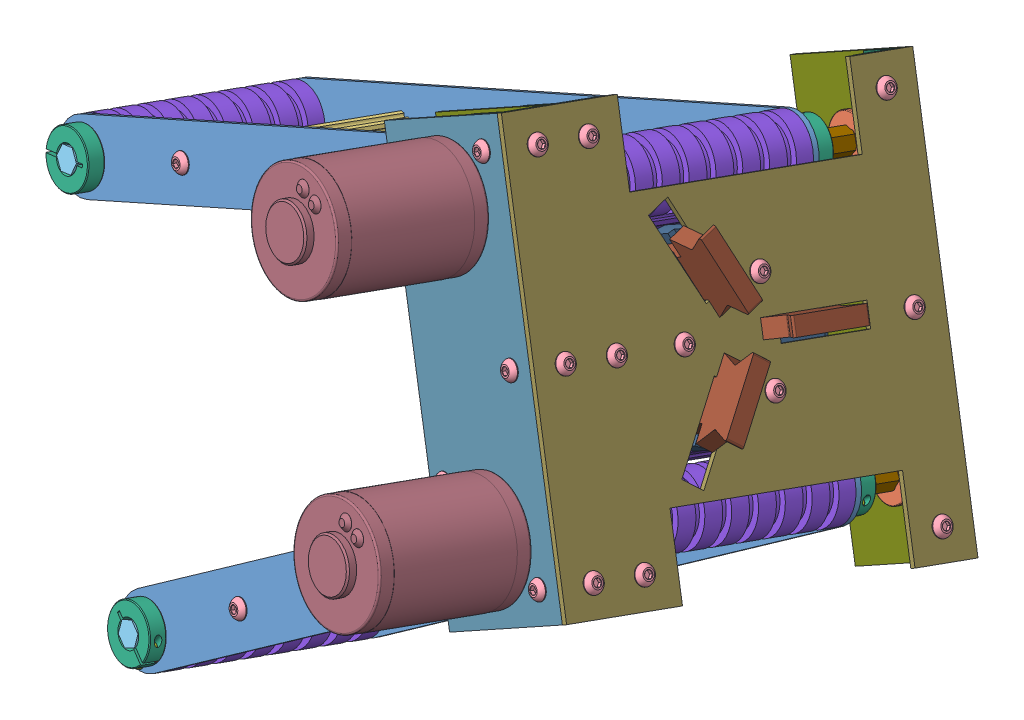
SolidWorks assembly 1504_Deep_Space_Intake_Prototype_21, configuration Default. Lengths in mm.
Overall size (546.37 581.13 450.16).
127 component instances, 18 part files, 4 mates.
Components (placement in the parent):
- Arm_Assembly-1: Arm_Assembly [Default] at (-225.8877 51.6666 438.0477) x (0.575434 0.811998 -0.097649) z (-0.800065 0.534132 -0.273127) size (386.7 241.43 173.84)
  - Arms_Top_Bottom_Plate-1: Arms_Top_Bottom_Plate [Default] at (-277.9606 169.7769 222.1703) x (-0.345233 0 -0.938517) z (0 -1 0) size (38.57 397.35 3.17)
  - 1_2_Hex_Bore_Flange_Bearing-1: 1_2_Hex_Bore_Flange_Bearing [Default] at (58.7558 163.3736 98.3094) x (0.284409 0 0.958703) z (0 1 0) size (31.12 31.12 7.93)
  - 1_2_Hex_Bore_Flange_Bearing-2: 1_2_Hex_Bore_Flange_Bearing [Default] at (-277.9606 163.3736 222.1703) x (-0.84433 0 -0.535824) z (0 1 0) size (31.12 31.12 7.93)
  - 1_2_Hex_Bore_Flange_Bearing-3: 1_2_Hex_Bore_Flange_Bearing [Default] at (-277.9606 49.4043 222.1703) x (0.84433 0 0.535824) z (0 -1 0) size (31.12 31.12 7.93)
  - 1_2_Hex_Bore_Flange_Bearing-4: 1_2_Hex_Bore_Flange_Bearing [Default] at (58.7558 49.4043 98.3094) x (-0.284409 0 -0.958703) z (0 -1 0) size (31.12 31.12 7.93)
  - Arms_Top_Bottom_Plate-2: Arms_Top_Bottom_Plate [Default] at (-277.9606 43.0009 222.1703) x (0.345233 0 0.938517) z (0 1 0) size (38.57 397.35 3.17)
  - 1_2_5__Churro_Tube-1: 1_2_5__Churro_Tube [Default] at (-209.5369 98.8759 197.0007) x (-0.345233 0 -0.938517) z (0 1 0) size (14.66 12.7 120.43)
  - 1_2_5__Churro_Tube-2: 1_2_5__Churro_Tube [Default] at (-109.6024 98.8759 160.2399) x (-0.345233 0 -0.938517) z (0 1 0) size (14.66 12.7 120.43)
  - 1_2_5__Churro_Tube-3: 1_2_5__Churro_Tube [Default] at (-9.6679 98.8759 123.479) x (-0.345233 0 -0.938517) z (0 1 0) size (14.66 12.7 120.43)
  - 1_4-20_1_2_Button_Cap-1: 1_4-20_1_2_Button_Cap [Default] at (-9.6679 173.1297 123.479) x (-0.345233 0 -0.938517) z (0 1 0) size (11.17 11.22 17.01)
  - 1_4-20_1_2_Button_Cap-2: 1_4-20_1_2_Button_Cap [Default] at (-109.6024 173.1297 160.2399) x (-0.345233 0 -0.938517) z (0 1 0) size (11.17 11.22 17.01)
  - 1_4-20_1_2_Button_Cap-3: 1_4-20_1_2_Button_Cap [Default] at (-209.5369 173.1297 197.0007) x (-0.345233 0 -0.938517) z (0 1 0) size (11.17 11.22 17.01)
  - 1_4-20_1_2_Button_Cap-4: 1_4-20_1_2_Button_Cap [Default] at (-9.6679 39.6481 123.479) x (-0.345233 0 -0.938517) z (0 -1 0) size (11.17 11.22 17.01)
  - 1_4-20_1_2_Button_Cap-5: 1_4-20_1_2_Button_Cap [Default] at (-109.6024 39.6481 160.2399) x (-0.345233 0 -0.938517) z (0 -1 0) size (11.17 11.22 17.01)
  - 1_4-20_1_2_Button_Cap-6: 1_4-20_1_2_Button_Cap [Default] at (-209.5369 39.6481 197.0007) x (-0.345233 0 -0.938517) z (0 -1 0) size (11.17 11.22 17.01)
  - 0.5_Hex_Shaft_Idle-1: 0.5_Hex_Shaft_Idle [Default] at (-271.2056 40.7057 219.3585) x (-0.384298 0 -0.923209) z (0.923209 0 -0.384298) size (13.49 146 14.63)
  - 1_2_Hex_Shaft_Collar-1: 1_2_Hex_Shaft_Collar [Default] at (127.7816 408.0678 12.6986) size (42.94 10.19 42.95)
    - am-1238 Clamp Only-1: am-1238 Clamp Only [Default] at (-405.7309 -236.7669 209.4653) x (0.868523 0 -0.495649) z (0.495649 0 0.868523) size (31.47 10.19 31.5)
    - am-1238 Screw Only_91251A194-1: am-1238 Screw Only_91251A194 [Default] at (-392.5372 -232.0044 210.8557) x (0.868523 0 -0.495649) z (0.495649 0 0.868523) size (6.86 6.86 17.11)
  - 1_2_Hex_Shaft_Collar_1-1: 1_2_Hex_Shaft_Collar_1 [Default] at (75.9024 412.9384 -146.8237) size (32.06 10.19 32.03)
    - am-1238 Clamp Only-1: am-1238 Clamp Only [Default] at (-353.863 -379.4625 368.9941) x (0.017972 0 -0.999838) z (0.999838 0 0.017972) size (31.47 10.19 31.5)
    - am-1238 Screw Only_91251A194-1: am-1238 Screw Only_91251A194 [Default] at (-345.9237 -374.7 358.3651) x (0.017972 0 -0.999838) z (0.999838 0 0.017972) size (6.86 6.86 17.11)
  - Belt_Hub-1: Belt_Hub [Default] at (-277.9606 48.8891 222.1703) x (-0.384298 0 -0.923209) z (0 1 0) size (38.57 38.57 113.97)
  - 0.5_Hex_Shaft_Drive-1: 0.5_Hex_Shaft_Drive [Default] at (51.8162 4.5177 95.9906) x (-0.316916 0 0.948454) z (-0.948454 0 -0.316916) size (13.49 241.43 14.63)
  - Belt_Hub-2: Belt_Hub [Default] at (58.7558 52.1174 98.3094) x (-0.316916 0 0.948454) z (0 1 0) size (38.57 38.57 113.97)
  - 1_2_Hex_Shaft_Collar_2-1: 1_2_Hex_Shaft_Collar_2 [Default] at (-0.3501 536.1995 139.4112) size (39.15 10.19 39.13)
    - am-1238 Clamp Only-1: am-1238 Clamp Only [Default] at (59.1023 -364.8986 -41.1142) x (-0.284409 0 -0.958703) z (0.958703 0 -0.284409) size (31.47 10.19 31.5)
    - am-1238 Screw Only_91251A194-1: am-1238 Screw Only_91251A194 [Default] at (63.4663 -360.1361 -53.6427) x (-0.284409 0 -0.958703) z (0.958703 0 -0.284409) size (6.86 6.86 17.11)
  - 1_2_Hex_Shaft_Collar_3-1: 1_2_Hex_Shaft_Collar_3 [Default] at (56.7879 209.4764 105.0462) size (39.15 10.19 39.13)
    - am-1238 Clamp Only-1: am-1238 Clamp Only [Default] at (1.968 -177.5245 -6.7368) x (-0.284409 0 -0.958703) z (0.958703 0 -0.284409) size (31.47 10.19 31.5)
    - am-1238 Screw Only_91251A194-1: am-1238 Screw Only_91251A194 [Default] at (6.332 -172.762 -19.2653) x (-0.284409 0 -0.958703) z (0.958703 0 -0.284409) size (6.86 6.86 17.11)
- Assem42^1504_Deep_Space_Intake_Prototype_21-1: Assem42^1504_Deep_Space_Intake_Prototype_21 [Default] at (-311.8417 180.9149 296.0777) x (-0.467037 0.835919 -0.288299) z (0.867816 0.49586 0.031899) size (230 332.1 111.03) (virtual)
  - Air_Gripper_Assembly-1: Air_Gripper_Assembly [Default] x (0 0 -1) z (1 0 0) size (100.53 94.6 107)
    - Air_Gripper_Body-1: Air_Gripper_Body [Default] at (2.7288 -0.6305 1.3862) size (74.5 90.6 101.7)
    - Air_Gripper_Grip-1: Air_Gripper_Grip [Default] at (-58.2712 16.3695 30.831) x (1 0 0) z (0 0.866025 -0.5) size (49.23 44 20)
    - Air_Gripper_Grip-2: Air_Gripper_Grip [Default] at (-58.2712 -34.6305 1.3862) size (49.23 44 20)
    - Air_Gripper_Grip-3: Air_Gripper_Grip [Default] at (-58.2712 16.3695 -28.0587) x (1 0 0) z (0 0.866025 0.5) size (49.23 44 20)
  - Intake_Front_Plate-1: Intake_Front_Plate [Default] at (0 0 71.7712) size (230 230 3.17)
  - Intake_Top_Plate_Assembly-1: Intake_Top_Plate_Assembly [Default] x (0 0 1) z (-1 0 0) size (85 125.82 230)
    - Mini_Cim-1: Mini_Cim [Default] at (24.7712 115 -75) x (0 1 0) z (-1 0 0) size (125.82 64.01 64.01)
    - Intake_Top_Plate-1: Intake_Top_Plate [Default] at (29.2712 115 0) x (0 -1 0) z (0 0 1) size (3.17 85 230)
    - Mini_Cim-2: Mini_Cim [Default] at (24.7712 115 75) x (0 1 0) z (-1 0 0) size (125.82 64.01 64.01)
  - Intake_1_Angle-1: Intake_1_Angle [Default] at (-115 111.825 71.7712) x (1 0 0) z (0 0 -1) size (230 25.4 25.4)
  - Intake_1_Angle-2: Intake_1_Angle [Default] at (-115 83.25 71.7712) x (1 0 0) z (0 0 -1) size (230 25.4 25.4)
  - Intake_Top_Bearing_Plate_Assembly-1: Intake_Top_Bearing_Plate_Assembly [Default] x (0 1 0) z (-1 0 0) size (7.93 85 230)
    - 1_2_Hex_Bore_Flange_Bearing-1: 1_2_Hex_Bore_Flange_Bearing [Default] at (80.5297 -24.7712 75) x (0 0.715549 0.698562) z (1 0 0) size (31.12 31.12 7.93)
    - Intake_Top_Bottom_Bearing_Plate-1: Intake_Top_Bottom_Bearing_Plate [Default] at (83.25 -29.2712 0) size (3.17 85 230)
    - 1_2_Hex_Bore_Flange_Bearing-2: 1_2_Hex_Bore_Flange_Bearing [Default] at (80.5297 -24.7712 -75) x (0 -0.16623 0.986087) z (1 0 0) size (31.12 31.12 7.93)
  - Intake_1_Angle-3: Intake_1_Angle [Default] at (-115 -111.825 71.7712) x (1 0 0) z (0 1 0) size (230 25.4 25.4)
  - Intake_Top_Bearing_Plate_Assembly_1-1: Intake_Top_Bearing_Plate_Assembly_1 [Default] at (0 -175 0) x (0 -1 0) z (1 0 0) size (7.93 85 230)
    - 1_2_Hex_Bore_Flange_Bearing-1: 1_2_Hex_Bore_Flange_Bearing [Default] at (-65.8953 -24.7712 75) x (0 0.16623 0.986087) z (1 0 0) size (31.12 31.12 7.93)
    - Intake_Top_Bottom_Bearing_Plate-1: Intake_Top_Bottom_Bearing_Plate [Default] at (-63.175 -29.2712 0) size (3.17 85 230)
    - 1_2_Hex_Bore_Flange_Bearing-2: 1_2_Hex_Bore_Flange_Bearing [Default] at (-65.8953 -24.7712 -75) x (0 -0.715549 0.698562) z (1 0 0) size (31.12 31.12 7.93)
  - 1_2_7.8__Churro_Tube-1: 1_2_7.8__Churro_Tube [Default] at (48.5 18.699 -3.2288) x (1 0 0) z (0 1 0) size (14.66 12.7 198.25)
  - 1_2_7.8__Churro_Tube-2: 1_2_7.8__Churro_Tube [Default] at (-48.5 18.699 -3.2288) x (1 0 0) z (0 1 0) size (14.66 12.7 198.25)
  - 1_2_1__Churro_Tube-1: 1_2_1__Churro_Tube [Default] at (-48.5 216.949 -3.2288) x (1 0 0) z (0 1 0) size (14.66 12.7 25.4)
  - 1_2_1__Churro_Tube-2: 1_2_1__Churro_Tube [Default] at (48.5 216.949 -3.2288) x (1 0 0) z (0 1 0) size (14.66 12.7 25.4)
  - 1_2_Hex_Shaft_Collar_8-1: 1_2_Hex_Shaft_Collar_8 [Default] at (-17.2542 -136.0955 -57.1098) size (38.28 10.19 38.3)
    - am-1238 Clamp Only-1: am-1238 Clamp Only [Default] at (-57.7458 19.0635 81.881) x (0.968965 0 -0.247198) z (-0.247198 0 -0.968965) size (31.47 10.19 31.5)
    - am-1238 Screw Only_91251A194-1: am-1238 Screw Only_91251A194 [Default] at (-49.2252 14.301 71.7122) x (0.968965 0 -0.247198) z (-0.247198 0 -0.968965) size (6.86 6.86 17.11)
  - 1_2_Hex_Shaft_Collar_9-1: 1_2_Hex_Shaft_Collar_9 [Default] at (26.9774 -156.866 11.2972) size (36.27 10.19 36.29)
    - am-1238 Clamp Only-1: am-1238 Clamp Only [Default] at (48.0098 39.834 13.4762) x (-0.986087 0 0.16623) z (0.16623 0 0.986087) size (31.47 10.19 31.5)
    - am-1238 Screw Only_91251A194-1: am-1238 Screw Only_91251A194 [Default] at (38.6776 35.0715 22.9057) x (-0.986087 0 0.16623) z (0.16623 0 0.986087) size (6.86 6.86 17.11)
  - 1_2_Hex_Shaft_Collar_10-1: 1_2_Hex_Shaft_Collar_10 [Default] at (-23.7492 -9.7763 -31.088) size (36.27 10.19 36.29)
    - am-1238 Clamp Only-1: am-1238 Clamp Only [Default] at (98.7365 107.7583 55.8614) x (-0.986087 0 0.16623) z (0.16623 0 0.986087) size (31.47 10.19 31.5)
    - am-1238 Screw Only_91251A194-1: am-1238 Screw Only_91251A194 [Default] at (89.4042 102.9958 65.2909) x (-0.986087 0 0.16623) z (0.16623 0 0.986087) size (6.86 6.86 17.11)
  - 1_2_Hex_Shaft_Collar_11-1: 1_2_Hex_Shaft_Collar_11 [Default] at (-73.8312 105.2973 -77.358) size (44.52 10.19 44.52)
    - am-1238 Clamp Only-1: am-1238 Clamp Only [Default] at (-1.1779 -7.3153 102.1199) x (-0.698562 0 -0.715549) z (-0.715549 0 0.698562) size (31.47 10.19 31.5)
    - am-1238 Screw Only_91251A194-1: am-1238 Screw Only_91251A194 [Default] at (-14.2447 -12.0778 99.8253) x (-0.698562 0 -0.715549) z (-0.715549 0 0.698562) size (6.86 6.86 17.11)
  - 1_4-20_1_2_Button_Cap-1: 1_4-20_1_2_Button_Cap [Default] at (48.5 118.3528 -3.2288) x (1 0 0) z (0 1 0) size (11.17 11.22 17.01)
  - 1_4-20_1_2_Button_Cap-2: 1_4-20_1_2_Button_Cap [Default] at (-48.5 118.3528 -3.2288) x (1 0 0) z (0 1 0) size (11.17 11.22 17.01)
  - 1_4-20_1_2_Button_Cap-3: 1_4-20_1_2_Button_Cap [Default] at (98.571 118.3528 57.4832) x (1 0 0) z (0 1 0) size (11.17 11.22 17.01)
  - 1_4-20_1_2_Button_Cap-4: 1_4-20_1_2_Button_Cap [Default] at (0 118.3528 57.4832) x (1 0 0) z (0 1 0) size (11.17 11.22 17.01)
  - 1_4-20_1_2_Button_Cap-5: 1_4-20_1_2_Button_Cap [Default] at (-98.571 118.3528 57.4832) x (1 0 0) z (0 1 0) size (11.17 11.22 17.01)
  - 1_4-20_1_2_Button_Cap-6: 1_4-20_1_2_Button_Cap [Default] at (48.5 -118.3528 -3.2288) x (1 0 0) z (0 -1 0) size (11.17 11.22 17.01)
  - 1_4-20_1_2_Button_Cap-7: 1_4-20_1_2_Button_Cap [Default] at (-48.5 -118.3528 -3.2288) x (1 0 0) z (0 -1 0) size (11.17 11.22 17.01)
  - 1_4-20_1_2_Button_Cap-8: 1_4-20_1_2_Button_Cap [Default] at (0 31 78.299) size (11.17 11.22 17.01)
  - 1_4-20_1_2_Button_Cap-9: 1_4-20_1_2_Button_Cap [Default] at (26.8464 -15.5007 78.299) size (11.17 11.22 17.01)
  - 1_4-20_1_2_Button_Cap-10: 1_4-20_1_2_Button_Cap [Default] at (-26.8476 -15.5 78.299) size (11.17 11.22 17.01)
  - 1_4-20_1_2_Button_Cap-11: 1_4-20_1_2_Button_Cap [Default] at (-98.571 68.962 78.299) size (11.17 11.22 17.01)
  - 1_4-20_1_2_Button_Cap-12: 1_4-20_1_2_Button_Cap [Default] at (0 68.962 78.299) size (11.17 11.22 17.01)
  - 1_4-20_1_2_Button_Cap-13: 1_4-20_1_2_Button_Cap [Default] at (98.571 68.962 78.299) size (11.17 11.22 17.01)
  - 1_4-20_1_2_Button_Cap-14: 1_4-20_1_2_Button_Cap [Default] at (-98.571 97.537 78.299) size (11.17 11.22 17.01)
  - 1_4-20_1_2_Button_Cap-15: 1_4-20_1_2_Button_Cap [Default] at (0 97.537 78.299) size (11.17 11.22 17.01)
  - 1_4-20_1_2_Button_Cap-16: 1_4-20_1_2_Button_Cap [Default] at (98.571 97.537 78.299) size (11.17 11.22 17.01)
  - 1_4-20_1_2_Button_Cap-17: 1_4-20_1_2_Button_Cap [Default] at (-98.571 -97.537 78.299) size (11.17 11.22 17.01)
  - 1_4-20_1_2_Button_Cap-18: 1_4-20_1_2_Button_Cap [Default] at (0 -97.537 78.299) size (11.17 11.22 17.01)
  - 1_4-20_1_2_Button_Cap-19: 1_4-20_1_2_Button_Cap [Default] at (98.571 -97.537 78.299) size (11.17 11.22 17.01)
  - 1_4-20_1_2_Button_Cap-20: 1_4-20_1_2_Button_Cap [Default] at (0 76.7222 57.4837) x (1 0 0) z (0 -1 0) size (11.17 11.22 17.01)
  - 1_4-20_1_2_Button_Cap-21: 1_4-20_1_2_Button_Cap [Default] at (99.6667 76.7222 57.4837) x (1 0 0) z (0 -1 0) size (11.17 11.22 17.01)
  - 1_4-20_1_2_Button_Cap-22: 1_4-20_1_2_Button_Cap [Default] at (-99.6667 76.7222 57.4837) x (1 0 0) z (0 -1 0) size (11.17 11.22 17.01)
  - 1_4-20_1_2_Button_Cap-23: 1_4-20_1_2_Button_Cap [Default] at (98.571 -118.3528 57.4832) x (1 0 0) z (0 -1 0) size (11.17 11.22 17.01)
  - 1_4-20_1_2_Button_Cap-24: 1_4-20_1_2_Button_Cap [Default] at (0 -118.3528 57.4832) x (1 0 0) z (0 -1 0) size (11.17 11.22 17.01)
  - 1_4-20_1_2_Button_Cap-25: 1_4-20_1_2_Button_Cap [Default] at (-98.571 -118.3528 57.4832) x (1 0 0) z (0 -1 0) size (11.17 11.22 17.01)
- Arm_Assembly_1-1: Arm_Assembly_1 [Default] at (-363.1275 377.5163 333.6092) x (-0.96906 0.136861 -0.205406) z (-0.179308 -0.96224 0.204798) size (349.83 241.43 256.87)
  - Arms_Top_Bottom_Plate-1: Arms_Top_Bottom_Plate [Default] at (254.6361 169.7769 301.2241) x (-0.565577 0 0.824696) z (0 -1 0) size (38.57 397.35 3.17)
  - 1_2_Hex_Bore_Flange_Bearing-1: 1_2_Hex_Bore_Flange_Bearing [Default] at (-41.2442 163.3736 98.3094) x (-0.99727 0 -0.073836) z (0 1 0) size (31.12 31.12 7.93)
  - 1_2_Hex_Bore_Flange_Bearing-2: 1_2_Hex_Bore_Flange_Bearing [Default] at (254.6361 163.3736 301.2241) x (0.800289 0 -0.599615) z (0 1 0) size (31.12 31.12 7.93)
  - 1_2_Hex_Bore_Flange_Bearing-3: 1_2_Hex_Bore_Flange_Bearing [Default] at (254.6361 49.4043 301.2241) x (-0.800289 0 0.599615) z (0 -1 0) size (31.12 31.12 7.93)
  - 1_2_Hex_Bore_Flange_Bearing-4: 1_2_Hex_Bore_Flange_Bearing [Default] at (-41.2442 49.4043 98.3094) x (0.99727 0 0.073836) z (0 -1 0) size (31.12 31.12 7.93)
  - Arms_Top_Bottom_Plate-2: Arms_Top_Bottom_Plate [Default] at (254.6361 43.0009 301.2241) x (0.565577 0 -0.824696) z (0 1 0) size (38.57 397.35 3.17)
  - 1_2_5__Churro_Tube-1: 1_2_5__Churro_Tube [Default] at (194.5106 98.8759 259.9901) x (-0.565577 0 0.824696) z (0 1 0) size (14.66 12.7 120.43)
  - 1_2_5__Churro_Tube-2: 1_2_5__Churro_Tube [Default] at (106.696 98.8759 199.7668) x (-0.565577 0 0.824696) z (0 1 0) size (14.66 12.7 120.43)
  - 1_2_5__Churro_Tube-3: 1_2_5__Churro_Tube [Default] at (18.8813 98.8759 139.5435) x (-0.565577 0 0.824696) z (0 1 0) size (14.66 12.7 120.43)
  - 1_4-20_1_2_Button_Cap-1: 1_4-20_1_2_Button_Cap [Default] at (18.8813 173.1297 139.5435) x (-0.565577 0 0.824696) z (0 1 0) size (11.17 11.22 17.01)
  - 1_4-20_1_2_Button_Cap-2: 1_4-20_1_2_Button_Cap [Default] at (106.696 173.1297 199.7668) x (-0.565577 0 0.824696) z (0 1 0) size (11.17 11.22 17.01)
  - 1_4-20_1_2_Button_Cap-3: 1_4-20_1_2_Button_Cap [Default] at (194.5106 173.1297 259.9901) x (-0.565577 0 0.824696) z (0 1 0) size (11.17 11.22 17.01)
  - 1_4-20_1_2_Button_Cap-4: 1_4-20_1_2_Button_Cap [Default] at (18.8813 39.6481 139.5435) x (-0.565577 0 0.824696) z (0 -1 0) size (11.17 11.22 17.01)
  - 1_4-20_1_2_Button_Cap-5: 1_4-20_1_2_Button_Cap [Default] at (106.696 39.6481 199.7668) x (-0.565577 0 0.824696) z (0 -1 0) size (11.17 11.22 17.01)
  - 1_4-20_1_2_Button_Cap-6: 1_4-20_1_2_Button_Cap [Default] at (194.5106 39.6481 259.9901) x (-0.565577 0 0.824696) z (0 -1 0) size (11.17 11.22 17.01)
  - 0.5_Hex_Shaft_Idle-1: 0.5_Hex_Shaft_Idle [Default] at (254.8713 40.7057 308.5372) x (0.999483 0 -0.032149) z (0.032149 0 0.999483) size (13.49 146 14.63)
  - 1_2_Hex_Shaft_Collar_4-1: 1_2_Hex_Shaft_Collar_4 [Default] at (127.7816 408.0678 12.6986) size (36.01 10.19 35.99)
    - am-1238 Clamp Only-1: am-1238 Clamp Only [Default] at (126.8565 -236.7669 288.5384) x (0.155654 0 0.987812) z (-0.987812 0 0.155654) size (31.47 10.19 31.5)
    - am-1238 Screw Only_91251A194-1: am-1238 Screw Only_91251A194 [Default] at (120.8803 -232.0044 300.3828) x (0.155654 0 0.987812) z (-0.987812 0 0.155654) size (6.86 6.86 17.11)
  - 1_2_Hex_Shaft_Collar_5-1: 1_2_Hex_Shaft_Collar_5 [Default] at (75.9024 412.9384 -146.8237) size (40.91 10.19 40.93)
    - am-1238 Clamp Only-1: am-1238 Clamp Only [Default] at (178.7337 -379.4625 448.0479) x (0.928566 0 0.371168) z (-0.371168 0 0.928566) size (31.47 10.19 31.5)
    - am-1238 Screw Only_91251A194-1: am-1238 Screw Only_91251A194 [Default] at (185.8588 -374.7 459.2389) x (0.928566 0 0.371168) z (-0.371168 0 0.928566) size (6.86 6.86 17.11)
  - Belt_Hub-1: Belt_Hub [Default] at (254.6361 48.8891 301.2241) x (0.999483 0 -0.032149) z (0 1 0) size (38.57 38.57 113.97)
  - 0.5_Hex_Shaft_Drive-1: 0.5_Hex_Shaft_Drive [Default] at (-36.6163 4.5177 92.642) x (-0.774565 0 -0.632494) z (0.632494 0 -0.774565) size (13.49 241.43 14.63)
  - Belt_Hub-2: Belt_Hub [Default] at (-41.2442 52.1174 98.3094) x (-0.774565 0 -0.632494) z (0 1 0) size (38.57 38.57 113.97)
  - 1_2_Hex_Shaft_Collar_6-1: 1_2_Hex_Shaft_Collar_6 [Default] at (-0.3501 536.1995 139.4112) size (33.71 10.19 33.73)
    - am-1238 Clamp Only-1: am-1238 Clamp Only [Default] at (-40.8811 -364.8986 -41.1008) x (0.99727 0 0.073836) z (-0.073836 0 0.99727) size (31.47 10.19 31.5)
    - am-1238 Screw Only_91251A194-1: am-1238 Screw Only_91251A194 [Default] at (-30.7126 -360.1361 -32.5798) x (0.99727 0 0.073836) z (-0.073836 0 0.99727) size (6.86 6.86 17.11)
  - 1_2_Hex_Shaft_Collar_7-1: 1_2_Hex_Shaft_Collar_7 [Default] at (56.7879 209.4764 105.0462) size (33.71 10.19 33.73)
    - am-1238 Clamp Only-1: am-1238 Clamp Only [Default] at (-98.032 -177.5245 -6.7368) x (0.99727 0 0.073836) z (-0.073836 0 0.99727) size (31.47 10.19 31.5)
    - am-1238 Screw Only_91251A194-1: am-1238 Screw Only_91251A194 [Default] at (-87.8635 -172.762 1.7842) x (0.99727 0 0.073836) z (-0.073836 0 0.99727) size (6.86 6.86 17.11)
Mates (geometry in assembly coordinates):
- Concentric1: concentric anti-aligned: cylinder of Arm_Assembly_1-1/0.5_Hex_Shaft_Drive-1 through (-341.2619 277.9329 364.8933) axis (0.169621 -0.235292 -0.957009) radius 4; cylinder of Assem42^1504_Deep_Space_Intake_Prototype_21-1/Intake_Top_Plate_Assembly-1/Mini_Cim-1 through (-344.879 282.9505 385.3015) axis (-0.169621 0.235292 0.957009) radius 4
- Coincident1: coincident anti-aligned: plane of Assem42^1504_Deep_Space_Intake_Prototype_21-1/Intake_Top_Plate_Assembly-1/Mini_Cim-1 through (-346.0687 285.353 380.3203) normal (0.169621 -0.235292 -0.957009); plane of Arm_Assembly_1-1/0.5_Hex_Shaft_Drive-1 through (-344.2005 282.0093 381.4734) normal (-0.169621 0.235292 0.957009)
- Concentric2: concentric anti-aligned: cylinder of Arm_Assembly-1/0.5_Hex_Shaft_Drive-1 through (-271.2063 152.5451 408.1381) axis (0.169621 -0.235292 -0.957009) radius 4; cylinder of Assem42^1504_Deep_Space_Intake_Prototype_21-1/Intake_Top_Plate_Assembly-1/Mini_Cim-2 through (-274.8234 157.5627 428.5463) axis (-0.169621 0.235292 0.957009) radius 4
- Coincident2: coincident anti-aligned: plane of Arm_Assembly-1/0.5_Hex_Shaft_Drive-1 through (-274.1449 156.6215 424.7182) normal (-0.169621 0.235292 0.957009); plane of Assem42^1504_Deep_Space_Intake_Prototype_21-1/Intake_Top_Plate_Assembly-1/Mini_Cim-2 through (-276.0131 159.9652 423.565) normal (0.169621 -0.235292 -0.957009)
